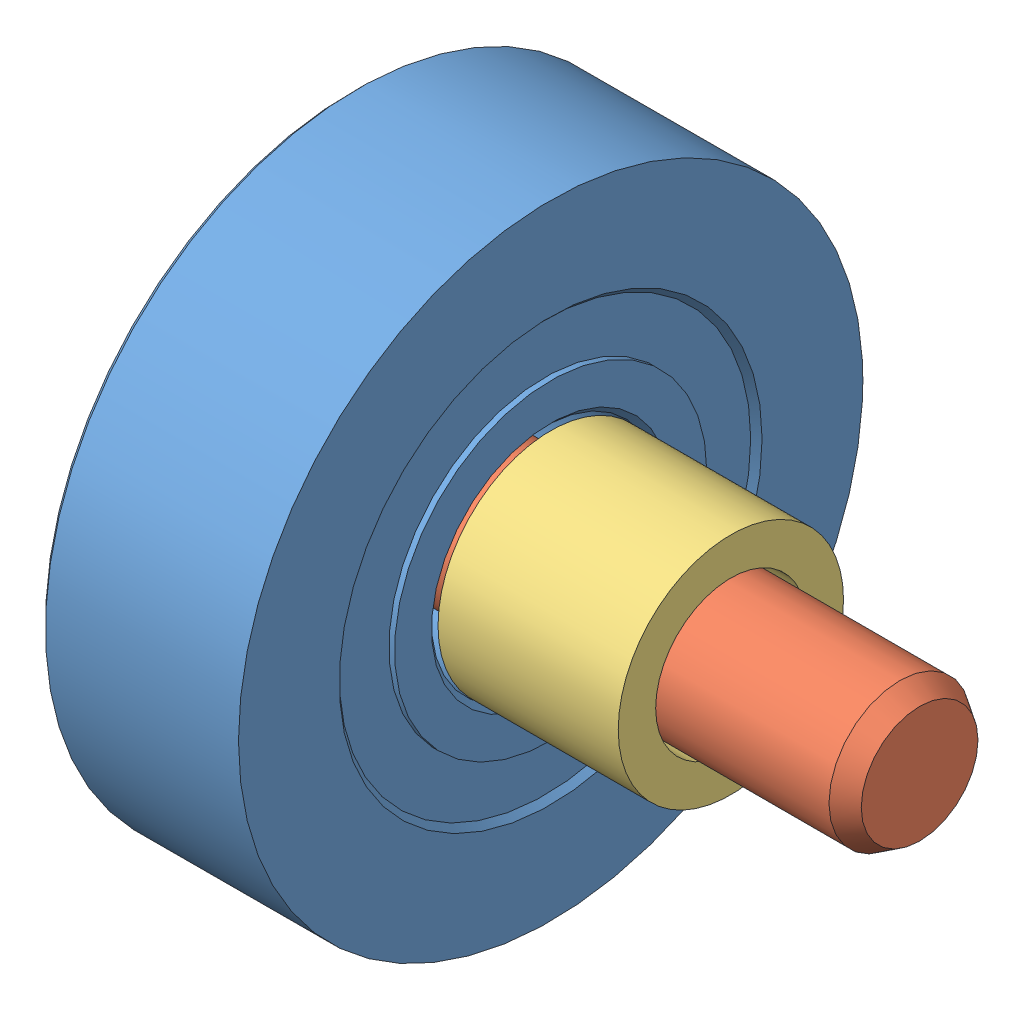
SolidWorks assembly Y Bearing, configuration Default. Lengths in mm.
Overall size (21.75 22 22).
3 component instances, 3 part files, 4 mates.
Components (placement in the parent):
- Ball Bearing 608Z-1: Ball Bearing 608Z [Default] at (-3.6619 16.75 -2.107) size (7 22 22)
- 5mm Low Profile Socket Head Screw-2: 5mm Low Profile Socket Head Screw [5mm x 20mm Low Profile Screw] at (-8.9119 16.75 -2.107) size (21.75 9.5 9.5)
- Nylon Spacer-3: Nylon Spacer [.25 inch] at (-0.1619 16.75 -2.107) size (6.35 7.94 7.94)
Mates (geometry in assembly coordinates):
- Concentric3: concentric anti-aligned: cylinder of Ball Bearing 608Z-1 through (-7.1619 16.75 -2.107) axis (1 0 0) radius 4; cylinder of 5mm Low Profile Socket Head Screw-2 through (-8.9119 16.75 -2.107) axis (-1 0 0) radius 2.5
- Coincident4: coincident anti-aligned: plane of Ball Bearing 608Z-1 through (-7.1619 16.75 -2.107) normal (-1 0 0); plane of 5mm Low Profile Socket Head Screw-2 through (-7.1619 19.25 -2.107) normal (1 0 0)
- Coincident5: coincident anti-aligned: plane of Ball Bearing 608Z-1 through (-0.1619 16.75 -2.107) normal (1 0 0); plane of Nylon Spacer-3 through (-0.1619 16.75 -2.107) normal (-1 0 0)
- Concentric4: concentric aligned: cylinder of 5mm Low Profile Socket Head Screw-2 through (-8.9119 16.75 -2.107) axis (-1 0 0) radius 2.5; cylinder of Nylon Spacer-3 through (6.1881 16.75 -2.107) axis (-1 0 0) radius 2.65
